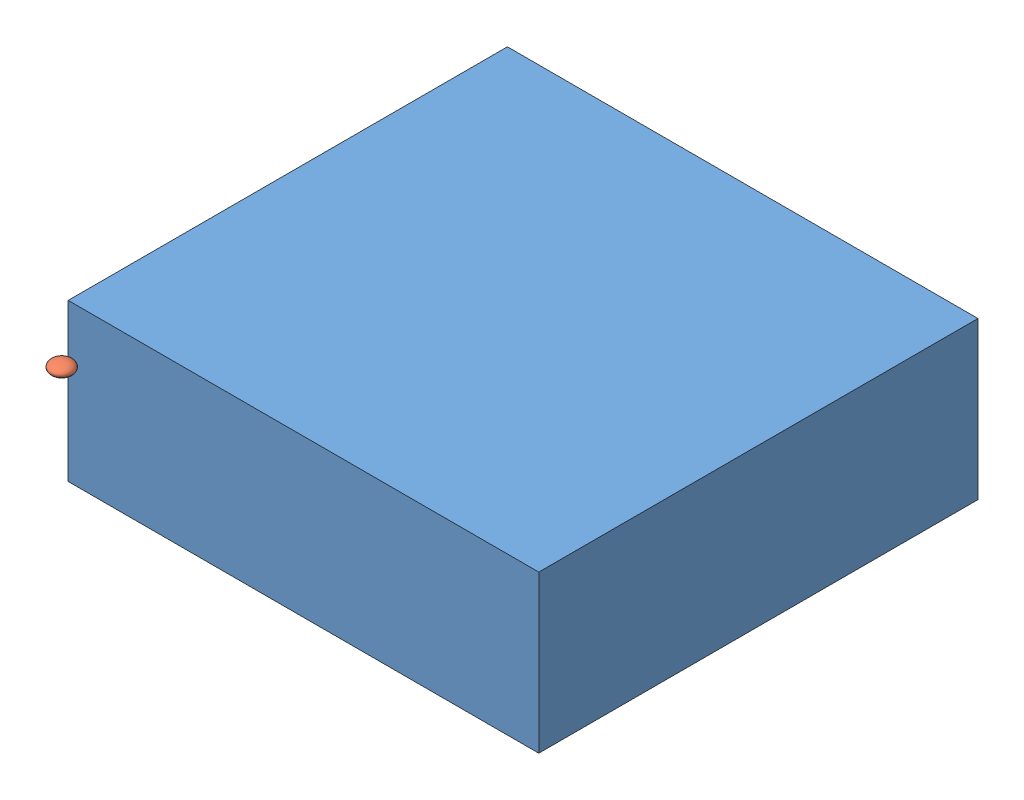
SolidWorks assembly Assem1, configuration Default. Lengths in mm.
Overall size (454.5 151.5 486.84).
2 component instances, 2 part files, 0 mates.
Components (placement in the parent):
- gobantraditional-1: gobantraditional [Default] at (101.874 158.3348 386.7383) size (454.5 151.5 424.2)
- stoneblack-1: stoneblack [Default] at (-79.7032 302.9926 650.7307) size (21.5 11 21.5)
